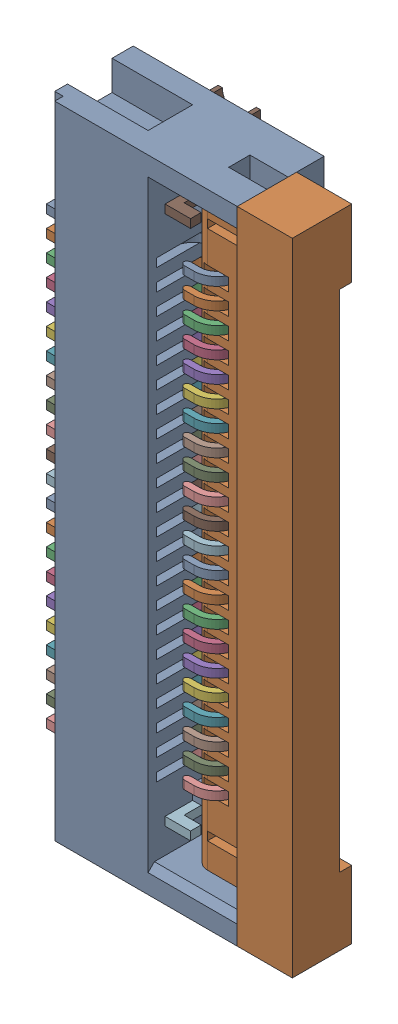
SolidWorks assembly J11, configuration Default. Lengths in mm.
Overall size (6.5 15.1 2.25).
27 component instances, 5 part files, 0 mates.
Components (placement in the parent):
- 687122149022-1: 687122149022 [Default] at (137.65 70.6501 0.7318) x (0 1 0) z (0 0 1) size (15.1 6.5 2.25)
  - 6871xx149022_Pin-1: 6871xx149022_Pin [Default] at (5.35 1.125 0.2986) x (-1 0 0) z (0 0 -1) size (0.2 4.6 2.25)
  - 6871xx149022_Pin-2: 6871xx149022_Pin [Default] at (4.85 1.125 0.2986) x (-1 0 0) z (0 0 -1) size (0.2 4.6 2.25)
  - 6871xx149022_Pin-3: 6871xx149022_Pin [Default] at (4.35 1.125 0.2986) x (-1 0 0) z (0 0 -1) size (0.2 4.6 2.25)
  - 6871xx149022_Pin-4: 6871xx149022_Pin [Default] at (3.85 1.125 0.2986) x (-1 0 0) z (0 0 -1) size (0.2 4.6 2.25)
  - 6871xx149022_Pin-5: 6871xx149022_Pin [Default] at (3.35 1.125 0.2986) x (-1 0 0) z (0 0 -1) size (0.2 4.6 2.25)
  - 6871xx149022_Pin-6: 6871xx149022_Pin [Default] at (2.85 1.125 0.2986) x (-1 0 0) z (0 0 -1) size (0.2 4.6 2.25)
  - 6871xx149022_Pin-7: 6871xx149022_Pin [Default] at (2.35 1.125 0.2986) x (-1 0 0) z (0 0 -1) size (0.2 4.6 2.25)
  - 6871xx149022_Pin-8: 6871xx149022_Pin [Default] at (1.85 1.125 0.2986) x (-1 0 0) z (0 0 -1) size (0.2 4.6 2.25)
  - 6871xx149022_Pin-9: 6871xx149022_Pin [Default] at (1.35 1.125 0.2986) x (-1 0 0) z (0 0 -1) size (0.2 4.6 2.25)
  - 6871xx149022_Pin-10: 6871xx149022_Pin [Default] at (0.85 1.125 0.2986) x (-1 0 0) z (0 0 -1) size (0.2 4.6 2.25)
  - 6871xx149022_Pin-11: 6871xx149022_Pin [Default] at (0.35 1.125 0.2986) x (-1 0 0) z (0 0 -1) size (0.2 4.6 2.25)
  - 6871xx149022_Pin-12: 6871xx149022_Pin [Default] at (-0.15 1.125 0.2986) x (-1 0 0) z (0 0 -1) size (0.2 4.6 2.25)
  - 6871xx149022_Pin-13: 6871xx149022_Pin [Default] at (-0.65 1.125 0.2986) x (-1 0 0) z (0 0 -1) size (0.2 4.6 2.25)
  - 6871xx149022_Pin-14: 6871xx149022_Pin [Default] at (-1.15 1.125 0.2986) x (-1 0 0) z (0 0 -1) size (0.2 4.6 2.25)
  - 6871xx149022_Pin-15: 6871xx149022_Pin [Default] at (-1.65 1.125 0.2986) x (-1 0 0) z (0 0 -1) size (0.2 4.6 2.25)
  - 6871xx149022_Pin-16: 6871xx149022_Pin [Default] at (-2.15 1.125 0.2986) x (-1 0 0) z (0 0 -1) size (0.2 4.6 2.25)
  - 6871xx149022_Pin-17: 6871xx149022_Pin [Default] at (-2.65 1.125 0.2986) x (-1 0 0) z (0 0 -1) size (0.2 4.6 2.25)
  - 6871xx149022_Pin-18: 6871xx149022_Pin [Default] at (-3.15 1.125 0.2986) x (-1 0 0) z (0 0 -1) size (0.2 4.6 2.25)
  - 6871xx149022_Pin-19: 6871xx149022_Pin [Default] at (-3.65 1.125 0.2986) x (-1 0 0) z (0 0 -1) size (0.2 4.6 2.25)
  - 6871xx149022_Pin-20: 6871xx149022_Pin [Default] at (-4.15 1.125 0.2986) x (-1 0 0) z (0 0 -1) size (0.2 4.6 2.25)
  - 6871xx149022_Pin-21: 6871xx149022_Pin [Default] at (-4.65 1.125 0.2986) x (-1 0 0) z (0 0 -1) size (0.2 4.6 2.25)
  - 6871xx149022_Pin-22: 6871xx149022_Pin [Default] at (-5.15 1.125 0.2986) x (-1 0 0) z (0 0 -1) size (0.2 4.6 2.25)
  - 6871xx149022_Patte-1: 6871xx149022_Patte [Default] at (6.15 0.7 -0.125) x (-1 0 0) z (0 0 1) size (1.4 3.1 1.85)
  - 6871xx149022_Patte2-1: 6871xx149022_Patte2 [Default] at (-6.35 0.7 -0.125) x (-1 0 0) z (0 0 1) size (1.4 3.1 1.85)
  - 687122149022-1: 687122149022 [Default] at origin size (15.1 4.5 2.2)
  - 687122149022_Actuator-1: 687122149022_Actuator [Default] at (0 -2.25 0.4) x (1 0 0) z (0 -1 0) size (15.1 1.4 2.9)
